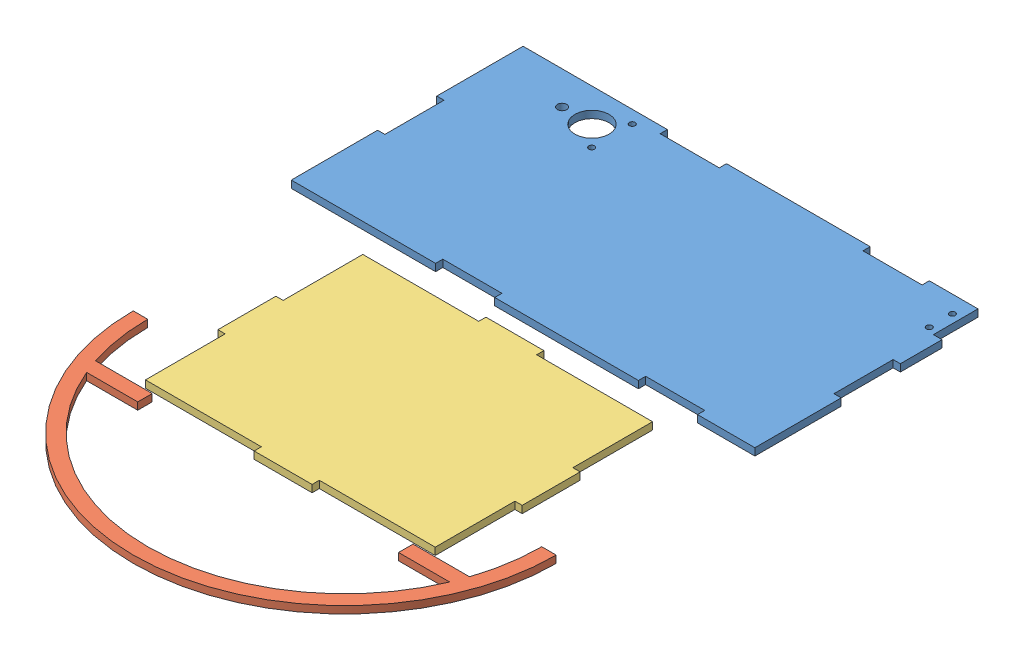
SolidWorks assembly Sheet 2, configuration Default. Lengths in mm.
Overall size (210 3.18 280).
3 component instances, 3 part files, 4 mates.
Components (placement in the parent):
- Long Side-1: Long Side [Default] at (40.5829 97.1911 2.6884) size (203.2 3.17 101.6)
- Bumper-1: Bumper [Default] at (72.9711 97.1911 138.2128) size (185.42 3.17 92.71)
- Short Side-1: Short Side [Default] at (8.2818 97.1911 116.838) size (133.35 3.17 101.6)
Mates (geometry in assembly coordinates):
- Coincident2: coincident anti-aligned: line of Long Side-1 through (28.5048 100.3661 -47.6737) axis (-1 0 0); line of assembly
- Coincident4: coincident aligned: line of Long Side-1 through (-34.7412 100.3661 16.0803) axis (0 0 1); line of assembly
- Coincident9: coincident: plane of Bumper-1 through (72.9711 100.3661 138.2128) normal (0 1 0); line of assembly
- Parallel1: parallel aligned: line of Bumper-1 through (-6.597 100.3661 171.7832) axis (1 0 0); line of assembly
